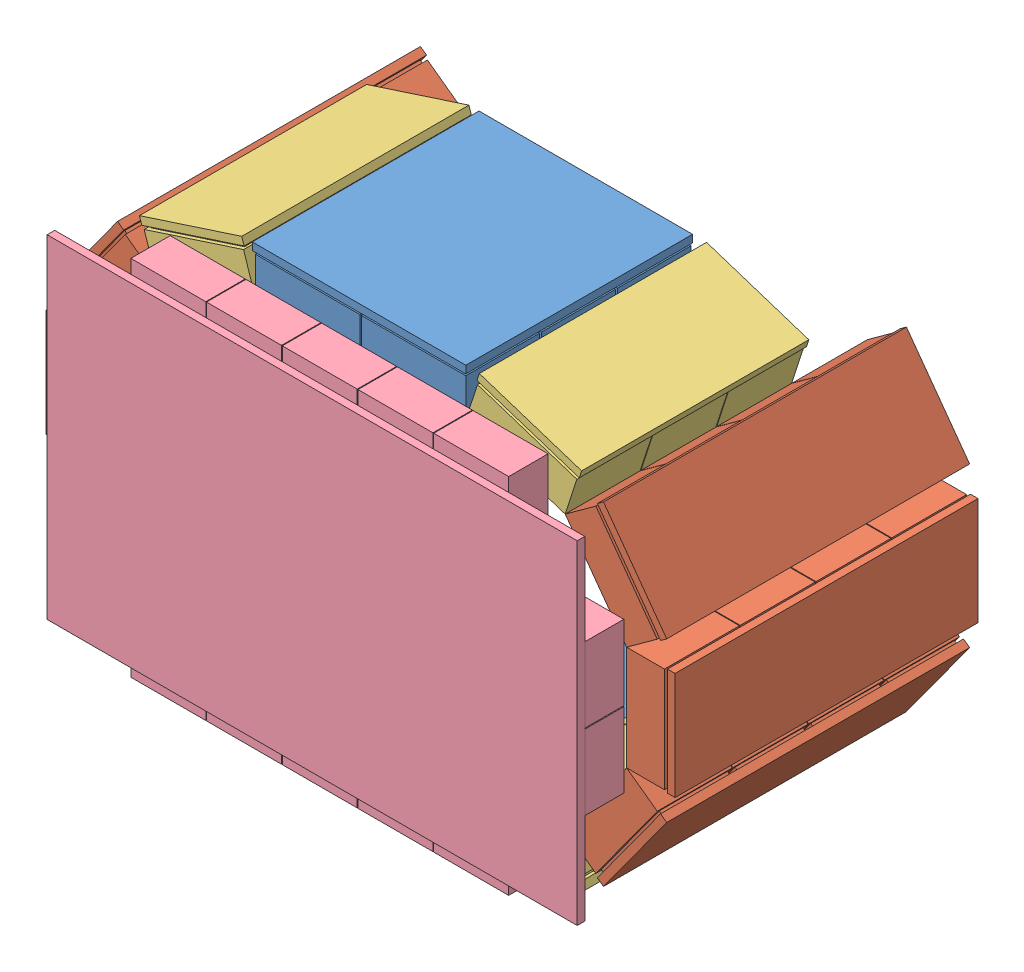
SolidWorks assembly Assem1, configuration Default. Lengths in mm.
Overall size (495.24 340.33 231).
16 component instances, 4 part files, 4 mates.
Components (placement in the parent):
- Detector1n2_changed-1: Detector1n2_changed [Default] at (192.5923 83.3442 236.3919) size (495.24 340.33 200.99)
  - top_bottomDetector2-1: top_bottomDetector2 [Default] at (5.3043 60.2155 74.3483) size (141 32 149.74)
  - CshapedDetector2-1: CshapedDetector2 [Default] at (104.3454 -76.5763 -85.899) x (0.951057 0.309017 0) z (0 0 1) size (177.89 270.84 200)
    - 1Detector-2: 1Detector [Default] at (173.0714 153.2337 184.2598) x (0.809017 0.587785 0) z (0 0 1) size (71 32 200)
    - 1Detector-4: 1Detector [Default] at (223.2683 222.3237 184.2598) x (0.309017 0.951057 0) z (0 0 1) size (71 32 200)
    - 1Detector-5: 1Detector [Default] at (223.2683 307.7237 184.2598) x (-0.309017 0.951057 0) z (0 0 1) size (71 32 200)
    - 1Detector_3modules-1: 1Detector_3modules [Default] at (91.8512 126.8436 209.2598) size (71 32 150)
    - 1Detector_3modules-2: 1Detector_3modules [Default] at (173.0714 376.8138 209.2598) x (-0.809017 0.587785 0) z (0 0 1) size (71 32 150)
  - CshapedDetector2-2: CshapedDetector2 [Default] at (-23.7368 484.2959 -85.899) x (-0.951057 -0.309017 0) z (0 0 1) size (177.89 270.84 200)
    - 1Detector-2: 1Detector [Default] at (173.0714 153.2337 184.2598) x (0.809017 0.587785 0) z (0 0 1) size (71 32 200)
    - 1Detector-4: 1Detector [Default] at (223.2683 222.3237 184.2598) x (0.309017 0.951057 0) z (0 0 1) size (71 32 200)
    - 1Detector-5: 1Detector [Default] at (223.2683 307.7237 184.2598) x (-0.309017 0.951057 0) z (0 0 1) size (71 32 200)
    - 1Detector_3modules-1: 1Detector_3modules [Default] at (91.8512 126.8436 209.2598) size (71 32 150)
    - 1Detector_3modules-2: 1Detector_3modules [Default] at (173.0714 376.8138 209.2598) x (-0.809017 0.587785 0) z (0 0 1) size (71 32 150)
  - top_bottomDetector2-2: top_bottomDetector2 [Default] at (75.3043 347.5042 74.3483) x (-1 0 0) z (0 0 1) size (141 32 149.74)
- Detector3-1: Detector3 [Default] at (231.9665 287.248 465.7527) x (0 -1 0) z (1 0 0) size (239.5 31 350)
Mates (geometry in assembly coordinates):
- Parallel1: parallel anti-aligned: line of Detector1n2_changed-1/top_bottomDetector2-1 through (163.3966 175.5597 434.7527) axis (1 0 0); line of Detector3-1 through (256.7165 166.848 434.7527) axis (-1 0 0)
- Perpendicular1: perpendicular: line of Detector1n2_changed-1/CshapedDetector2-1/1Detector-4 through (408.5767 252.704 385.2527) axis (0 0 1); line of Detector3-1 through (406.7165 336.748 434.7527) axis (0 -1 0)
- Coincident5: coincident anti-aligned: plane of Detector1n2_changed-1/top_bottomDetector2-2 through (232.3966 398.8484 434.7527) normal (0 0 1); plane of Detector3-1 through (231.9665 287.248 434.7527) normal (0 0 -1)
- Coincident6: coincident anti-aligned: line of Detector1n2_changed-1/CshapedDetector2-2/1Detector-4 through (57.2165 321.704 434.7527) axis (0 -1 0); line of Detector3-1 through (57.2165 287.348 434.7527) axis (0 1 0)
